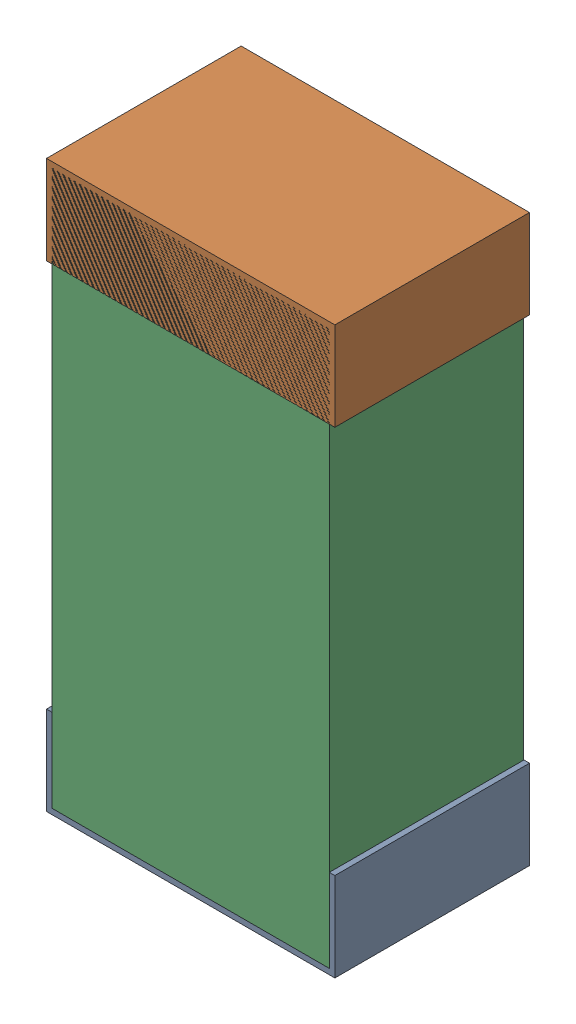
SolidWorks assembly R50, configuration Default. Lengths in mm.
Overall size (0.52 1.02 0.35).
6 component instances, 2 part files, 0 mates.
Components (placement in the parent):
- 870941120-1: 870941120 [Default] at (22.2242 30.5266 -1.9516) size (0.52 0.16 0.35)
  - Extruded_3-1: Extruded_3 [Default] at origin size (0.52 0.16 0.35)
- 870941120-2: 870941120 [Default] at (22.2242 31.3866 -1.9516) size (0.52 0.16 0.35)
  - Extruded_3-1: Extruded_3 [Default] at origin size (0.52 0.16 0.35)
- 870941280-1: 870941280 [Default] at (22.2242 30.9566 -1.9506) size (0.5 1 0.35)
  - Extruded_4-1: Extruded_4 [Default] at origin size (0.5 1 0.35)
